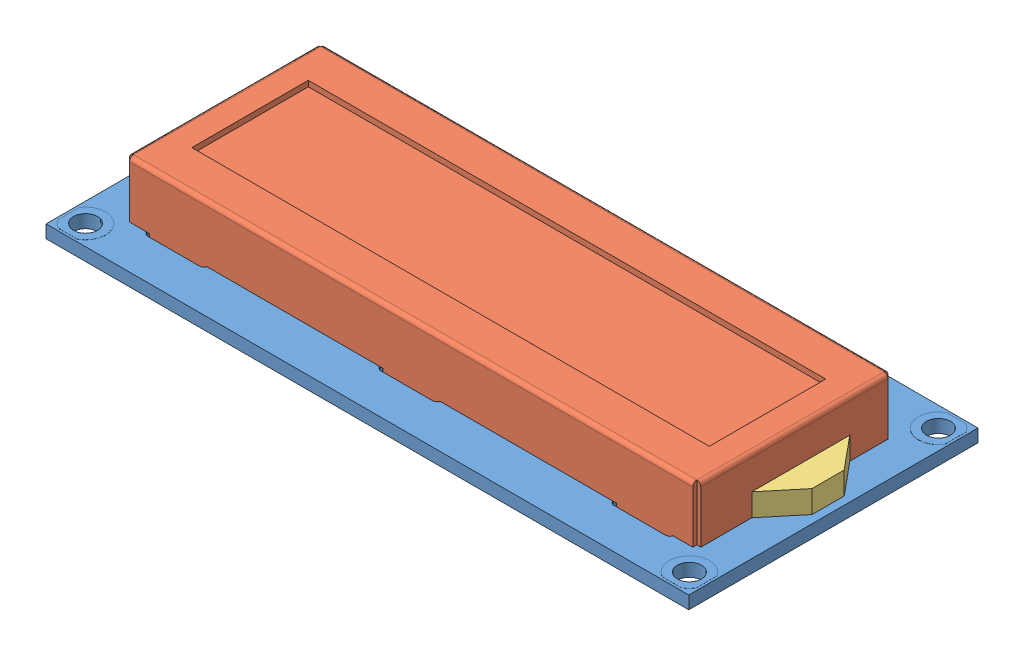
SolidWorks assembly LCD_ASM, configuration Défaut. Lengths in mm.
Overall size (80 10.8 36).
3 component instances, 3 part files, 5 mates.
Components (placement in the parent):
- LCD_board-1: LCD_board [Défaut] at (-43.5509 -1.9206 98) size (80 2.81 36)
- LCD_screen-1: LCD_screen [Défaut] at (-39.0509 -0.3206 92.6) size (71.1 10.8 24.3)
- LCD_backlight-1: LCD_backlight [Défaut] at (32.0491 -0.3206 73.5575) x (0 0 1) z (-1 0 0) size (12.2 2.8 3.4)
Mates (geometry in assembly coordinates):
- Coïncidente1: coincident anti-aligned: plane of LCD_board-1 through (-43.5509 -0.3206 98) normal (0 1 0); plane of LCD_screen-1 through (-39.0509 -0.3206 92.6) normal (0 -1 0)
- Distance1: distance = 5.4 mm aligned: plane of LCD_board-1 through (-43.5509 -0.3206 98) normal (0 0 1); plane of LCD_screen-1 through (-39.0509 6.6794 92.6) normal (0 0 1)
- Distance2: distance = 4.5 mm aligned: plane of LCD_screen-1 through (-39.0509 6.6794 92.6) normal (-1 0 0); plane of LCD_board-1 through (-43.5509 -0.3206 98) normal (-1 0 0)
- Coïncidente2: coincident anti-aligned: plane of LCD_screen-1 through (32.0491 6.6794 92.6) normal (1 0 0); plane of LCD_backlight-1 through (32.0491 -8.1479 73.5575) normal (-1 0 0)
- Coïncidente3: coincident anti-aligned: plane of LCD_board-1 through (-43.5509 -0.3206 98) normal (0 1 0); plane of LCD_backlight-1 through (32.0491 -0.3206 73.5575) normal (0 -1 0)
